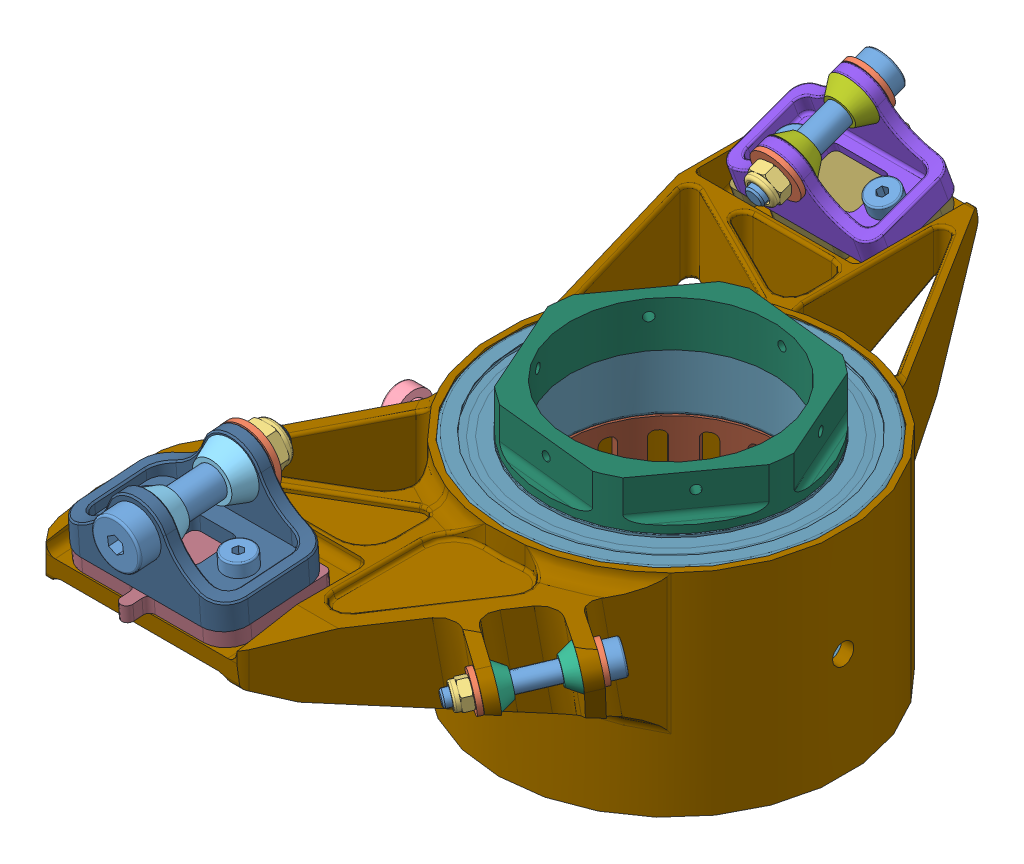
SolidWorks assembly LustroPUTM-S-SR-WT-Upright_Assembly, configuration Domyślna. Lengths in mm.
Overall size (178.33 100.25 263.89).
40 component instances, 15 part files, 0 mates.
Components (placement in the parent):
- LustroPUTM-FT-ELESA_ISO7379-1: LustroPUTM-FT-ELESA_ISO7379 [6-M5-16] at (-73.3121 52.3064 107.0039) x (0.000017 0.997564 0.069756) z (0.884401 0.032543 -0.465591) size (30 10 10)
- LustroPUTM-FT-FABORY_ISO7089-1: LustroPUTM-FT-FABORY_ISO7089 [M6 [38093.060.001]] at (-73.3124 32.3685 105.6097) x (0.995538 0.006566 -0.094128) z (0.000017 0.997564 0.069756) size (12 12 1.6)
- LustroPUTM-FT-FABORY_ISO7089-2: LustroPUTM-FT-FABORY_ISO7089 [M6 [38093.060.001]] at (-43.3124 32.3685 105.6025) x (0.999769 0.001482 -0.021432) z (0.000017 0.997564 0.069756) size (12 12 1.6)
- LustroPUTM-FT-FABORY_DIN985-1: LustroPUTM-FT-FABORY_DIN985 [M5 [12348.050.001]] at (-73.3124 30.7724 105.498) x (1 -0.000015 -0.000017) z (0.000017 0.997564 0.069756) size (9.51 8.27 5.13)
- LustroPUTM-FT-FABORY_DIN985-2: LustroPUTM-FT-FABORY_DIN985 [M5 [12348.050.001]] at (-43.3124 30.7724 105.4909) x (0.977913 -0.014596 0.208501) z (0.000017 0.997564 0.069756) size (9.51 8.27 5.13)
- LustroPUTM-FT-ELESA_ISO7379-2: LustroPUTM-FT-ELESA_ISO7379 [6-M5-16] at (-43.3121 52.3064 106.9967) x (0.000017 0.997564 0.069756) z (0.244546 -0.067643 0.967275) size (30 10 10)
- LustroPUTM-FT-ELESA_ISO7379-3: LustroPUTM-FT-ELESA_ISO7379 [6-M5-12] at (-43.3626 48.4996 -105.8246) x (0.000081 0.939693 0.34202) z (0.24445 -0.331663 0.911177) size (24.5 10 10)
- LustroPUTM-FT-FABORY_ISO7089-3: LustroPUTM-FT-FABORY_ISO7089 [M6 [38093.060.001]] at (-43.3638 34.0654 -111.0782) x (0.991092 0.045475 -0.125177) z (0.000081 0.939693 0.34202) size (12 12 1.6)
- LustroPUTM-FT-ELESA_ISO7379-4: LustroPUTM-FT-ELESA_ISO7379 [6-M5-12] at (-73.3626 48.5018 -105.8238) x (0.000081 0.939693 0.34202) z (0.879208 0.162884 -0.44773) size (24.5 10 10)
- LustroPUTM-FT-FABORY_DIN985-3: LustroPUTM-FT-FABORY_DIN985 [M5 [12348.050.001]] at (-43.3639 32.5619 -111.6255) x (0.981294 -0.065919 0.180877) z (0.000081 0.939693 0.34202) size (9.51 8.27 5.13)
- LustroPUTM-FT-FABORY_ISO7089-4: LustroPUTM-FT-FABORY_ISO7089 [M6 [38093.060.001]] at (-73.3638 34.0677 -111.0774) x (0.991092 0.045475 -0.125177) z (0.000081 0.939693 0.34202) size (12 12 1.6)
- LustroPUTM-FT-FABORY_DIN985-4: LustroPUTM-FT-FABORY_DIN985 [M5 [12348.050.001]] at (-73.3639 32.5642 -111.6246) x (0.981294 -0.065919 0.180877) z (0.000081 0.939693 0.34202) size (9.51 8.27 5.13)
- LustroPUTM-FT-ELESA_ISO7379-5: LustroPUTM-FT-ELESA_ISO7379 [10-M8-35] at (-58.306 59.0418 132.5323) x (0.000237 -0.069756 0.997564) z (-0.998312 -0.05795 -0.003815) size (55 16 16)
- LustroPUTM-FT-ELESA_ISO7379-6: LustroPUTM-FT-ELESA_ISO7379 [8-M6-30] at (-58.3615 68.7452 -121.9741) x (0 0.34202 -0.939693) z (0.971899 -0.221202 -0.080511) size (46.5 13 13)
- LustroPUTM-FT-FABORY_ISO7089-5: LustroPUTM-FT-FABORY_ISO7089 [M10 [38093.100.001]] at (-58.3162 62.0414 89.6371) x (0.999967 0.008078 0.000328) z (0.000237 -0.069756 0.997564) size (20 20 2)
- LustroPUTM-FT-FABORY_DIN985-5: LustroPUTM-FT-FABORY_DIN985 [M8 [12348.080.001]] at (-58.3167 62.1809 87.6419) x (1 0.000008 -0.000237) z (0.000237 -0.069756 0.997564) size (15.49 13.47 8.24)
- LustroPUTM-FT-FABORY_ISO7089-6: LustroPUTM-FT-FABORY_ISO7089 [M8 [38093.080.001]] at (-58.3615 66.3169 -115.3023) x (0.579316 -0.765946 -0.278782) z (0 -0.34202 0.939693) size (16 16 1.6)
- LustroPUTM-FT-FABORY_ISO7089-7: LustroPUTM-FT-FABORY_ISO7089 [M8 [38093.080.001]] at (-58.3615 55.509 -85.608) x (1 0 0) z (0 -0.34202 0.939693) size (16 16 1.6)
- LustroPUTM-FT-FABORY_DIN985-6: LustroPUTM-FT-FABORY_DIN985 [M6 [12348.060.001]] at (-58.3615 55.509 -85.608) x (-0.97819 -0.195184 -0.071041) z (0 0.34202 -0.939693) size (11.9 10.35 6.18)
- LustroPUTM-FT-ELESA_ISO7379-7: LustroPUTM-FT-ELESA_ISO7379 [6-M5-30] at (36.9117 38.4914 59.8402) x (0.549587 0.139173 -0.823763) z (0.832885 -0.16828 0.527242) size (44 10 10)
- LustroPUTM-FT-FABORY_ISO7089-8: LustroPUTM-FT-FABORY_ISO7089 [M6 [38093.060.001]] at (33.5592 37.6424 64.8651) x (0.822021 0.085913 0.562939) z (-0.549587 -0.139173 0.823763) size (12 12 1.6)
- LustroPUTM-FT-FABORY_ISO7089-9: LustroPUTM-FT-FABORY_ISO7089 [M6 [38093.060.001]] at (16.7418 33.3837 90.0723) x (0.83032 0.017968 0.556997) z (-0.549587 -0.139173 0.823763) size (12 12 1.6)
- LustroPUTM-FT-FABORY_DIN985-7: LustroPUTM-FT-FABORY_DIN985 [M5 [12348.050.001]] at (16.7418 33.3837 90.0723) x (-0.725389 -0.409657 -0.553166) z (0.549587 0.139173 -0.823763) size (9.51 8.27 5.13)
- LustroPUTM-FT-FABORY_DIN7984-1: LustroPUTM-FT-FABORY_DIN7984 [M8x45 [07090.080.045]] at (-125.3441 -14.416 -28.009) x (-1 0 0.000237) z (-0.00009 0.924506 -0.381168) size (50 13 13)
- LustroPUTM-FT-FABORY_DIN7984-2: LustroPUTM-FT-FABORY_DIN7984 [M8x45 [07090.080.045]] at (-125.3318 -14.416 23.991) x (-1 0 0.000237) z (-0.00009 0.924506 -0.381168) size (50 13 13)
- LustroPUTM-S-Grzybek_10mm_wyzszy-1: LustroPUTM-S-Grzybek_10mm_wyzszy [Domyślna] at (-58.3087 59.844 121.0603) x (1 0.000237 -0.000221) z (-0.000221 0.997564 0.069757) size (18 6.5 18)
- LustroPUTM-S-Grzybek_10mm_wyzszy-2: LustroPUTM-S-Grzybek_10mm_wyzszy [Domyślna] at (-58.3151 61.7275 94.1261) x (-0.938678 -0.343971 -0.02383) z (-0.344795 0.936386 0.06556) size (18 6.5 18)
- LustroPUTM-S-Grzybek_6mm-1: LustroPUTM-S-Grzybek_6mm [Domyślna] at (30.8112 36.9466 68.984) x (0.615605 0.59913 0.511932) z (0.564788 -0.788463 0.243598) size (13 4 13)
- LustroPUTM-S-Grzybek_6mm-2: LustroPUTM-S-Grzybek_6mm [Domyślna] at (19.8195 34.1631 85.4592) x (-0.832956 0.015359 -0.553125) z (0.064328 -0.990149 -0.124366) size (13 4 13)
- LustroPUTM-S-Grzybek_8mm-1: LustroPUTM-S-Grzybek_8mm [Domyślna] at (-58.3615 57.4243 -90.8703) x (0.992432 -0.115388 -0.041998) z (0.122793 0.932581 0.339432) size (16 5 16)
- LustroPUTM-S-Grzybek_8mm-2: LustroPUTM-S-Grzybek_8mm [Domyślna] at (-58.3615 64.9488 -111.5436) x (-0.985557 -0.15913 -0.057918) z (-0.169342 0.926121 0.337081) size (16 5 16)
- LustroPUTM-S-SR-WT-U-Clevis_Upper_10mm-1: LustroPUTM-S-SR-WT-U-Clevis_Upper_10mm [Domyślna] at (-58.3632 36.3227 -94.294) x (1 -0.000076 -0.000028) z (0 -0.34202 0.939693) size (50 29 30)
- LustroPUTM-S-SR-WT-Upright-1: LustroPUTM-S-SR-WT-Upright [Domyślna] at (-9.3379 48.584 -2.0366) x (0 -1 0) z (0.000237 0 1) size (70.71 141 248)
- LustroPUTM-S-SR-WT-U-Clevis_bottom-1: LustroPUTM-S-SR-WT-U-Clevis_bottom [Domyślna] at (-86.308 41.574 124.3004) x (1 0 -0.000237) z (0.000017 0.997564 0.069756) size (56 36 28)
- LustroPUTM-S-SR-WT-U-RearDistanceRing-1: LustroPUTM-S-SR-WT-U-RearDistanceRing [Domyślna] at (-9.3379 13.584 -2.0366) size (76 30 76)
- LustroPUTM-S-SR-WT-U-Shim_5mm-1: LustroPUTM-S-SR-WT-U-Shim_5mm [5 mm] at (-58.3632 41.453 -108.3894) x (1 -0.000076 -0.000028) z (0.000081 0.939693 0.34202) size (50 37 5)
- LustroPUTM-S-SR-WT-U-Shim_5mm_wiekszy-1: LustroPUTM-S-SR-WT-U-Shim_5mm_wiekszy [5 mm] at (-58.3123 37.8418 105.9888) x (1 0 -0.000237) z (-0.000017 -0.997564 -0.069756) size (56 42 5)
- LustroPUTM-S-SR-WT-Bearing-1: LustroPUTM-S-SR-WT-Bearing [Domyślna] at (-9.3379 28.584 -2.0366) x (0 1 0) z (0.143537 0 0.989645) size (20 110 110)
- LustroPUTM-S-SR-WT-Bearing-2: LustroPUTM-S-SR-WT-Bearing [Domyślna] at (-9.3379 -21.416 -2.0366) x (0 1 0) z (0 0 1) size (20 110 110)
- LustroPUTM-S-SR-WT-U-Hubnut-1: LustroPUTM-S-SR-WT-U-Hubnut [Domyślna] at (-9.3379 48.584 -2.0366) x (0.994417 0 0.105525) z (0 -1 0) size (82.6 82.6 15)
